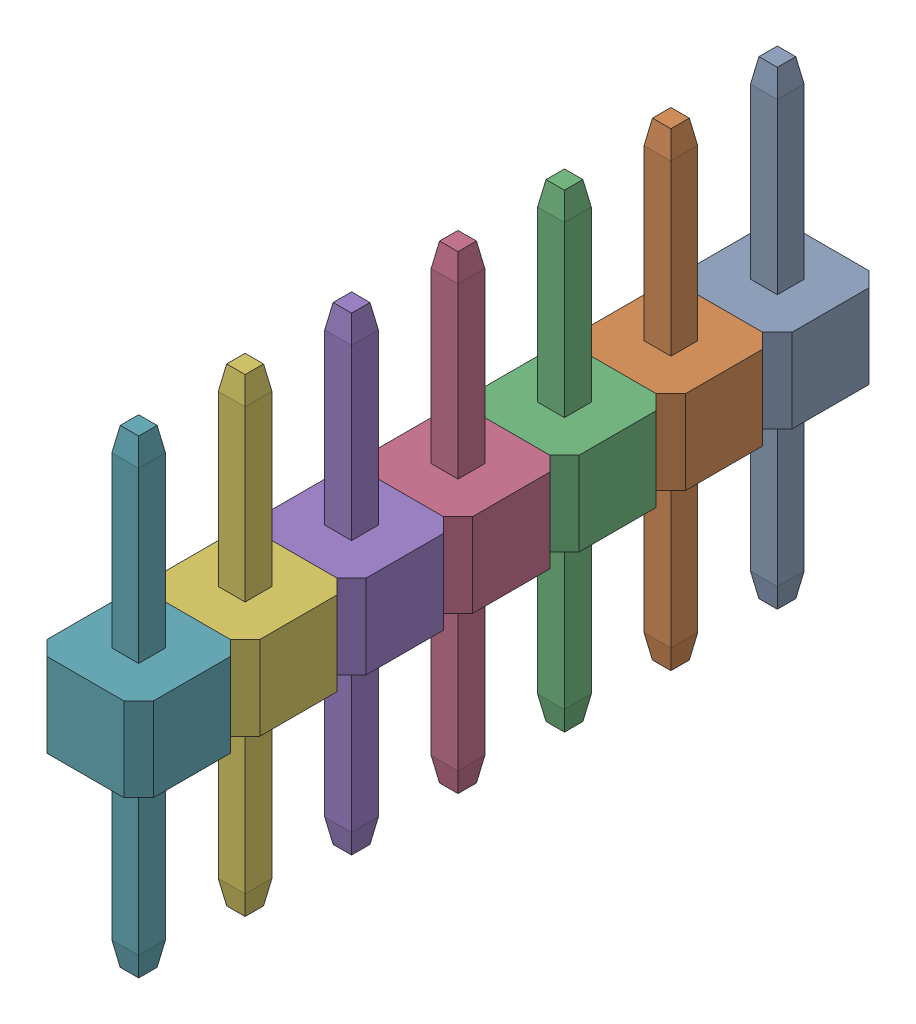
SolidWorks assembly PinHeaderMatrix, configuration Predeterminado. Lengths in mm.
Overall size (2.54 11.2 17.78).
7 component instances, 1 part files, 0 mates.
Components (placement in the parent):
- Single_pin_header-1: Single_pin_header [Predeterminado] at origin size (2.54 11.2 2.54)
- Single_pin_header-2: Single_pin_header [Predeterminado] at (0 0 2.54) size (2.54 11.2 2.54)
- Single_pin_header-3: Single_pin_header [Predeterminado] at (0 0 5.08) size (2.54 11.2 2.54)
- Single_pin_header-4: Single_pin_header [Predeterminado] at (0 0 7.62) size (2.54 11.2 2.54)
- Single_pin_header-5: Single_pin_header [Predeterminado] at (0 0 10.16) size (2.54 11.2 2.54)
- Single_pin_header-6: Single_pin_header [Predeterminado] at (0 0 12.7) size (2.54 11.2 2.54)
- Single_pin_header-7: Single_pin_header [Predeterminado] at (0 0 15.24) size (2.54 11.2 2.54)
